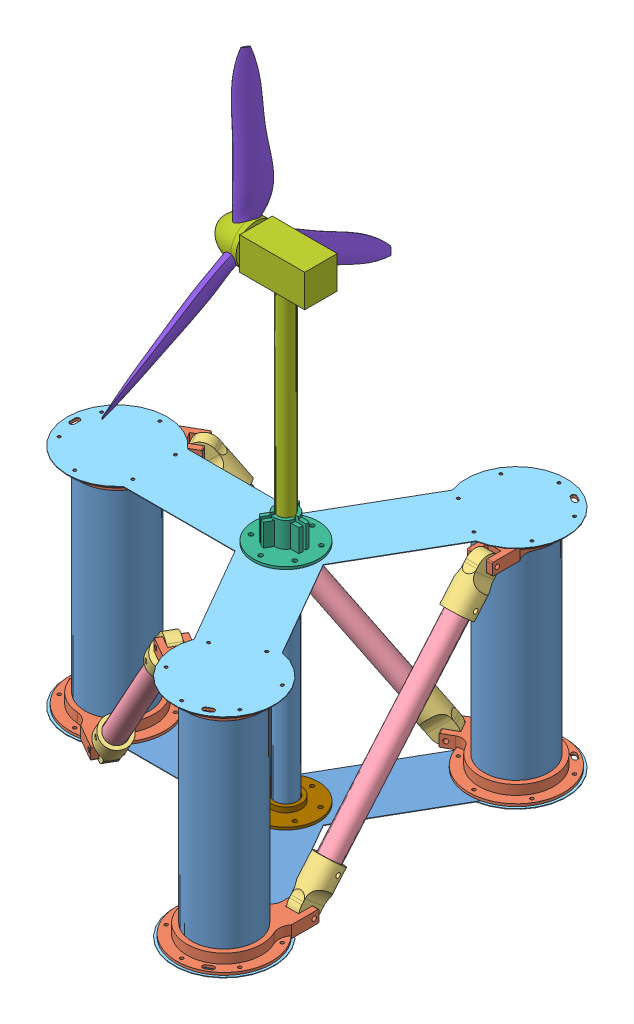
SolidWorks assembly Unsinkable5, configuration Default. Lengths in mm.
Overall size (757.98 1288.33 869.46).
26 component instances, 9 part files, 55 mates.
Components (placement in the parent):
- Base2heaveplate-1: Base2heaveplate [Default] at (311.77 321.3046 451.015) size (634.86 450.01 713.12)
- Heavebracketsingle-1: Heavebracketsingle [Default] at (480.3896 766.3146 158.9573) x (-0.5 0 0.866025) z (-0.866025 0 -0.5) size (190 24 215.8)
- Heavebracketsingle-2: Heavebracketsingle [Default] at (-25.4691 766.3146 451.015) size (190 24 215.8)
- Heavebracketsingle-3: Heavebracketsingle [Default] at (480.3896 766.3146 743.0726) x (-0.5 0 -0.866025) z (0.866025 0 -0.5) size (190 24 215.8)
- Heavebracketsingle-4: Heavebracketsingle [Default] at (480.3896 326.3146 743.0726) x (-0.5 0 -0.866025) z (-0.866025 0 0.5) size (190 24 215.8)
- Heavebracketsingle-5: Heavebracketsingle [Default] at (480.3896 326.3146 158.9573) x (-0.5 0 0.866025) z (0.866025 0 0.5) size (190 24 215.8)
- Heavebracketsingle-6: Heavebracketsingle [Default] at (-25.4691 326.3146 451.015) x (1 0 0) z (0 0 -1) size (190 24 215.8)
- Connector1-1: Connector1 [Default] at (315.1332 694.8549 700.5485) x (0.5 0 -0.866025) z (0.564517 0.75835 0.325924) size (55 55 99.99)
- Connector1-2: Connector1 [Default] at (526.1909 397.7744 578.6944) x (-1 0 0) z (0 -0.75835 0.651848) size (55 55 99.99)
- Connector1-3: Connector1 [Default] at (93.986 694.8549 329.1608) x (0.5 0 0.866025) z (-0.564517 0.75835 0.325924) size (55 55 99.99)
- Connector1-4: Connector1 [Default] at (315.1332 397.7744 201.4814) x (-0.5 0 -0.866025) z (0.564517 -0.75835 -0.325924) size (55 55 99.99)
- Connector1-5: Connector1 [Default] at (526.1909 694.8549 323.3356) x (-1 0 0) z (0 0.75835 -0.651848) size (55 55 99.99)
- Connector1-6: Connector1 [Default] at (93.986 397.7744 572.8691) x (-0.5 0 0.866025) z (-0.564517 -0.75835 -0.325924) size (55 55 99.99)
- pipe-2: pipe [Default] at (75.8193 719.2593 339.6493) x (0.221414 -0.241263 0.944864) z (0.564517 -0.75835 -0.325924) size (40 40 450)
- pipe-3: pipe [Default] at (77.6128 375.7792 563.4161) x (-0.5 0 0.866025) z (0.564517 0.75835 0.325924) size (40 40 450)
- pipe-4: pipe [Default] at (526.1909 724.804 297.5925) x (0.8735 0.317335 0.369183) z (0 -0.75835 0.651848) size (40 40 450)
- heave ho-3: heave ho [Default] at (311.77 771.3146 451.015) size (705.86 1 784.12)
- heave ho-4: heave ho [Default] at (311.77 320.3046 451.015) size (705.86 1 784.12)
- turbine_attachment_sld-1: turbine_attachment_sld [Default] at (311.77 772.3146 451.015) x (0.866025 0 0.5) z (0 1 0) size (130 130 55)
- turbie-1: turbie [Default] at (829.5178 692.8216 234.8314) x (0 0 1) z (-1 0 0) size (614.99 815.03 200)
  - Tower1-1: Tower1 [Default] at (216.1836 84.493 517.7478) size (80 522.5 200)
  - blade-1: blade [Default] at (217.4586 599.493 597.2478) x (0.866025 0 0.5) z (0 1 0) size (73.31 29.13 300.04)
  - blade-2: blade [Default] at (187.4003 551.8472 597.2478) x (-0.433013 0.75 0.5) z (-0.866025 -0.5 0) size (73.31 29.13 300.04)
  - blade-3: blade [Default] at (243.6919 549.6388 597.2478) x (-0.433013 -0.75 0.5) z (0.866025 -0.5 0) size (73.31 29.13 300.04)
- turbine_attachment_middle-1: turbine_attachment_middle [Default] at (311.77 321.3046 451.015) x (0.882051 0 -0.471154) z (0 1 0) size (130 130 15)
- turbine_attachment_middle-3: turbine_attachment_middle [Default] at (311.77 771.3146 451.015) x (0.866025 0 -0.5) z (0 -1 0) size (130 130 15)
Mates (geometry in assembly coordinates):
- Concentric1: concentric aligned: cylinder of Base2heaveplate-1 through (-25.4691 321.3146 451.015) axis (0 -1 0) radius 64.5; cylinder of Heavebracket-1 through (-11.0353 321.3046 451.015) axis (0 -1 0) radius 39.5
- Coincident1: coincident anti-aligned: plane of Base2heaveplate-1 through (480.3896 321.3046 158.9573) normal (0 -1 0); plane of Heavebracket-1 through (-11.0353 321.3046 451.015) normal (0 1 0)
- Concentric21: concentric aligned: cylinder of Base2heaveplate-1 through (480.3896 321.3146 743.0726) axis (0 -1 0) radius 64.5; cylinder of Heavebracketsingle-3 through (480.3896 771.3146 743.0726) axis (0 -1 0) radius 64.5
- Concentric22: concentric aligned: cylinder of Base2heaveplate-1 through (-25.4691 321.3146 451.015) axis (0 -1 0) radius 64.5; cylinder of Heavebracketsingle-2 through (-25.4691 771.3146 451.015) axis (0 -1 0) radius 64.5
- Concentric23: concentric aligned: cylinder of Base2heaveplate-1 through (480.3896 321.3146 158.9573) axis (0 -1 0) radius 64.5; cylinder of Heavebracketsingle-1 through (480.3896 771.3146 158.9573) axis (0 -1 0) radius 64.5
- Concentric24: concentric anti-aligned: cylinder of Base2heaveplate-1 through (480.3896 321.3146 158.9573) axis (0 -1 0) radius 64.5; cylinder of Heavebracketsingle-5 through (480.3896 321.3146 158.9573) axis (0 1 0) radius 64.5
- Coincident21: coincident anti-aligned: plane of Base2heaveplate-1 through (480.3896 321.3146 158.9573) normal (0 1 0); plane of Heavebracketsingle-5 through (480.3896 321.3146 158.9573) normal (0 -1 0)
- Concentric25: concentric anti-aligned: cylinder of Base2heaveplate-1 through (-25.4691 321.3146 451.015) axis (0 -1 0) radius 64.5; cylinder of Heavebracketsingle-6 through (-25.4691 321.3146 451.015) axis (0 1 0) radius 64.5
- Coincident22: coincident anti-aligned: plane of Base2heaveplate-1 through (480.3896 321.3146 158.9573) normal (0 1 0); plane of Heavebracketsingle-6 through (-25.4691 321.3146 451.015) normal (0 -1 0)
- Concentric26: concentric anti-aligned: cylinder of Base2heaveplate-1 through (480.3896 321.3146 743.0726) axis (0 -1 0) radius 64.5; cylinder of Heavebracketsingle-4 through (480.3896 321.3146 743.0726) axis (0 1 0) radius 64.5
- Coincident23: coincident anti-aligned: plane of Base2heaveplate-1 through (480.3896 321.3146 158.9573) normal (0 1 0); plane of Heavebracketsingle-4 through (480.3896 321.3146 743.0726) normal (0 -1 0)
- Concentric27: concentric aligned: cylinder of Heavebracketsingle-1 through (632.5066 759.3146 267.9285) axis (-1 0 0) radius 4.5; cylinder of Connector1-5 through (553.6909 759.3146 267.9285) axis (-1 0 0) radius 4.5
- Distance1: distance = 0.5 mm anti-aligned: plane of Part2-5 through (538.6909 754.7229 239.5751) normal (1 0 0); plane of Heavebracketsingle-1 through (539.1909 747.3146 248.9285) normal (-1 0 0)
- Concentric28: concentric anti-aligned: cylinder of Heavebracketsingle-5 through (309.9593 333.3146 81.7058) axis (0.5 0 0.866025) radius 4.5; cylinder of Connector1-4 through (376.8672 333.3146 197.5936) axis (-0.5 0 -0.866025) radius 4.5
- Distance2: distance = 0.5 mm anti-aligned: plane of Part2-4 through (361.7479 305.9724 189.0022) normal (0.5 0 0.866025); plane of Heavebracketsingle-5 through (360.9569 345.3146 190.0362) normal (-0.5 0 -0.866025)
- Concentric29: concentric aligned: cylinder of Heavebracketsingle-3 through (309.9593 759.3146 820.3242) axis (0.5 0 -0.866025) radius 4.5; cylinder of Connector1-1 through (349.3672 759.3146 752.0678) axis (0.5 0 -0.866025) radius 4.5
- Distance4: distance = 0.5 mm anti-aligned: plane of Part2-1 through (361.7479 786.6568 713.0278) normal (0.5 0 -0.866025); plane of Heavebracketsingle-3 through (360.9569 747.3146 711.9937) normal (-0.5 0 0.866025)
- Concentric30: concentric aligned: cylinder of Heavebracketsingle-4 through (632.5066 333.3146 634.1014) axis (-1 0 0) radius 4.5; cylinder of Connector1-2 through (553.6909 333.3146 634.1014) axis (-1 0 0) radius 4.5
- Distance5: distance = 0.5 mm anti-aligned: plane of Part2-2 through (513.6909 305.9724 625.3035) normal (-1 0 0); plane of Heavebracketsingle-4 through (513.1909 345.3146 624.1014) normal (1 0 0)
- Concentric31: concentric aligned: cylinder of Heavebracketsingle-2 through (-7.1558 759.3146 264.7922) axis (0.5 0 0.866025) radius 4.5; cylinder of Connector1-3 through (32.2521 759.3146 333.0486) axis (0.5 0 0.866025) radius 4.5
- Distance6: distance = 0.5 mm anti-aligned: plane of Part2-3 through (15.1973 754.7229 360.2157) normal (-0.5 0 -0.866025); plane of Heavebracketsingle-2 through (23.0476 747.3146 355.106) normal (0.5 0 0.866025)
- Concentric32: concentric anti-aligned: cylinder of Heavebracketsingle-6 through (-7.1558 333.3146 637.2377) axis (0.5 0 -0.866025) radius 4.5; cylinder of Connector1-6 through (59.7521 333.3146 521.3499) axis (-0.5 0 0.866025) radius 4.5
- Distance7: distance = 0.5 mm anti-aligned: plane of Part2-6 through (59.8714 305.9724 538.7393) normal (0.5 0 -0.866025); plane of Heavebracketsingle-6 through (61.1623 345.3146 538.9073) normal (-0.5 0 0.866025)
- Concentric33: concentric aligned: cylinder of Connector1-4 through (334.8913 371.2321 190.074) axis (-0.564517 0.75835 0.325924) radius 20.5; cylinder of pipe-2 through (329.8519 378.0019 192.9836) axis (-0.564517 0.75835 0.325924) radius 20
- Concentric34: concentric anti-aligned: cylinder of Connector1-3 through (74.2279 721.3972 340.5681) axis (0.564517 -0.75835 -0.325924) radius 20.5; cylinder of pipe-2 through (329.8519 378.0019 192.9836) axis (-0.564517 0.75835 0.325924) radius 20
- Concentric35: concentric anti-aligned: cylinder of Connector1-6 through (74.2279 371.2321 561.4618) axis (0.564517 0.75835 0.325924) radius 20.5; cylinder of pipe-3 through (331.6454 717.0366 710.0818) axis (-0.564517 -0.75835 -0.325924) radius 20
- Concentric36: concentric aligned: cylinder of Connector1-1 through (334.8913 721.3972 711.9559) axis (-0.564517 -0.75835 -0.325924) radius 20.5; cylinder of pipe-3 through (331.6454 717.0366 710.0818) axis (-0.564517 -0.75835 -0.325924) radius 20
- Concentric37: concentric anti-aligned: cylinder of Connector1-5 through (526.1909 721.3972 300.5209) axis (0 -0.75835 0.651848) radius 20.5; cylinder of pipe-4 through (526.1909 383.5466 590.9241) axis (0 0.75835 -0.651848) radius 20
- Concentric38: concentric aligned: cylinder of Connector1-2 through (526.1909 371.2321 601.5091) axis (0 0.75835 -0.651848) radius 20.5; cylinder of pipe-4 through (526.1909 383.5466 590.9241) axis (0 0.75835 -0.651848) radius 20
- Coincident32: coincident anti-aligned: plane of Heavebracketsingle-1 through (480.3896 771.3146 158.9573) normal (0 1 0); plane of heave ho-1 through (480.8317 773.3046 159.2082) normal (0 -1 0)
- Coincident33: coincident aligned: plane of Heavebracketsingle-1 through (516.0595 771.3146 87.1753) normal (0.5 0 -0.866025); plane of heave ho-1 through (516.4997 774.3046 87.4295) normal (0.5 0 -0.866025)
- Coincident34: coincident: plane of Heavebracketsingle-1 through (516.0595 771.3146 87.1753) normal (0.5 0 -0.866025); plane of heave ho-2 through (516.0595 774.3046 87.1753) normal (0.5 0 -0.866025)
- Coincident35: coincident: plane of Heavebracketsingle-1 through (480.3896 771.3146 158.9573) normal (0 1 0); plane of heave ho-2 through (480.3896 773.3046 158.9573) normal (0 -1 0)
- Concentric41: concentric: cylinder of Heavebracketsingle-3 through (480.3896 771.3146 828.0726) axis (0 -1 0) radius 3.25; cylinder of heave ho-2 through (480.3896 774.3046 828.0726) axis (0 -1 0) radius 3
- Concentric44: concentric anti-aligned: circle of Base2heaveplate-1; circle of heave ho-4
- Concentric45: concentric aligned: circle of Base2heaveplate-1; cylinder of heave ho-4 through (480.3896 321.3046 743.0726) axis (0 -1 0) radius 100
- Coincident37: coincident anti-aligned: plane of Base2heaveplate-1 through (480.3896 321.3046 158.9573) normal (0 -1 0); plane of heave ho-4 through (480.3896 321.3046 158.9573) normal (0 1 0)
- Coincident38: coincident anti-aligned: plane of heave ho-3 through (480.3896 772.3146 158.9573) normal (0 1 0); plane of turbine_attachment_sld-1 through (311.77 772.3146 451.015) normal (0 -1 0)
- Concentric48: concentric aligned: cylinder of turbine_attachment_sld-1 through (311.77 827.3146 451.015) axis (0 -1 0) radius 16.005; cylinder of turbie-1/Tower1-1 through (311.77 1227.3146 451.015) axis (0 -1 0) radius 16
- Coincident41: coincident anti-aligned: plane of turbine_attachment_sld-1 through (311.77 777.3146 451.015) normal (0 1 0); plane of turbie-1/Tower1-1 through (311.77 777.3146 451.015) normal (0 -1 0)
- Parallel4: parallel anti-aligned: plane of heave ho-3 through (274.5309 772.3146 515.515) normal (0 0 1); plane of turbie-1/Tower1-1 through (251.77 1292.3146 418.515) normal (0 0 -1)
- Concentric49: concentric anti-aligned: cylinder of Connector1-1 through (309.851 706.2302 729.2531) axis (0.5 0 -0.866025) radius 4.5; cylinder of pipe-3 through (333.601 706.2302 688.1169) axis (-0.5 0 0.866025) radius 4
- Concentric55: concentric anti-aligned: cylinder of heave ho-3 through (312.6194 772.3146 399.5438) axis (0 -1 0) radius 4; cylinder of turbine_attachment_sld-1 through (312.6194 767.3146 399.5438) axis (0 1 0) radius 4.25
- Concentric56: concentric anti-aligned: cylinder of heave ho-3 through (312.6194 772.3146 502.4861) axis (0 -1 0) radius 4; cylinder of turbine_attachment_sld-1 through (312.6194 767.3146 502.4861) axis (0 1 0) radius 4.25
- Concentric57: concentric anti-aligned: cylinder of Base2heaveplate-1 through (311.77 771.3146 451.015) axis (0 -1 0) radius 21; cylinder of turbine_attachment_middle-1 through (311.77 321.3046 451.015) axis (0 1 0) radius 22.5
- Coincident44: coincident aligned: plane of turbine_attachment_middle-1 through (311.77 321.3046 451.015) normal (0 -1 0); line of Base2heaveplate-1 through (424.5309 321.3046 775.3226) axis (-0.5 0 -0.866025)
- Concentric58: concentric anti-aligned: cylinder of heave ho-4 through (355.9207 321.3046 477.4861) axis (0 -1 0) radius 4; cylinder of turbine_attachment_middle-1 through (355.9207 316.3046 477.4861) axis (0 1 0) radius 4
- Coincident45: coincident: line of heave ho-3 through (50.9492 771.3146 515.515) axis (1 0 0); plane of turbine_attachment_middle-3 through (311.77 771.3146 451.015) normal (0 1 0)
- Concentric59: concentric aligned: cylinder of Base2heaveplate-1 through (311.77 771.3146 451.015) axis (0 -1 0) radius 21; cylinder of turbine_attachment_middle-3 through (311.77 771.3146 451.015) axis (0 -1 0) radius 22.5
- Concentric60: concentric anti-aligned: cylinder of turbine_attachment_sld-1 through (266.77 767.3146 426.015) axis (0 1 0) radius 4.25; cylinder of turbine_attachment_middle-3 through (266.77 776.3146 426.015) axis (0 -1 0) radius 4
- Coincident46: coincident anti-aligned: plane of Heavebracketsingle-2 through (-25.4691 771.3146 451.015) normal (0 1 0); plane of heave ho-3 through (480.3896 771.3146 158.9573) normal (0 -1 0)
- Coincident47: coincident aligned: circle of Base2heaveplate-1; circle of Heavebracketsingle-2
- Concentric63: concentric aligned: cylinder of Heavebracketsingle-2 through (-99.0812 771.3146 408.515) axis (0 -1 0) radius 3.25; cylinder of heave ho-3 through (-99.0812 772.3146 408.515) axis (0 -1 0) radius 3
- Coincident48: coincident anti-aligned: plane of Heavebracketsingle-3 through (480.3896 771.3146 743.0726) normal (0 1 0); plane of heave ho-3 through (480.3896 771.3146 158.9573) normal (0 -1 0)
- Coincident49: coincident anti-aligned: plane of Heavebracketsingle-1 through (480.3896 771.3146 158.9573) normal (0 1 0); plane of heave ho-3 through (480.3896 771.3146 158.9573) normal (0 -1 0)
